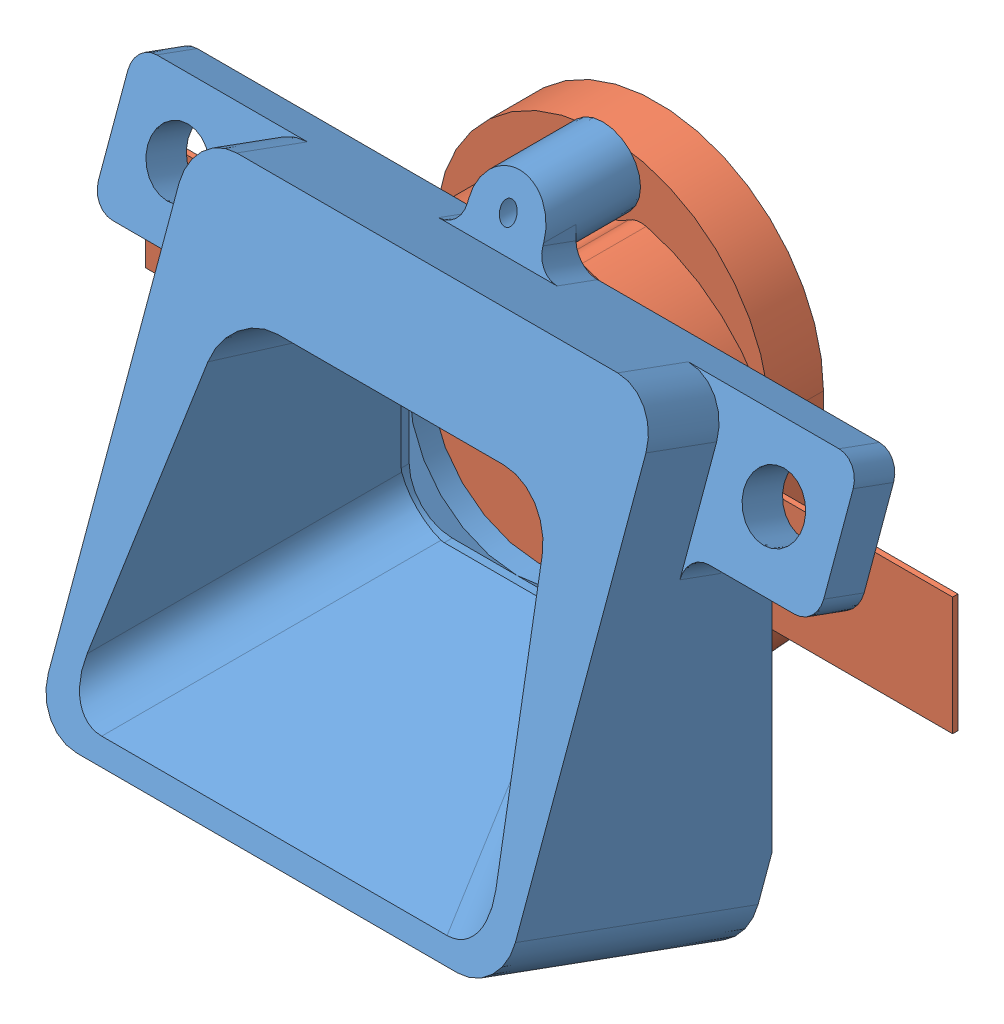
SolidWorks assembly setup_led, configuration Default. Lengths in mm.
Overall size (37.5 26.13 18.1).
2 component instances, 2 part files, 3 mates.
Components (placement in the parent):
- led hoder-1: led hoder [Default] at (21.4895 15.2859 17.3454) size (33.7 26.13 15.6)
- power_led_10W_1-1: power_led_10W_1 [Default] at (41.4895 29.1109 11.8454) x (0 -1 0) z (0 0 1) size (21.6 37.5 5.5)
Mates (geometry in assembly coordinates):
- Coincident1: coincident: plane of led hoder-1 through (21.4895 15.2859 17.3454) normal (0 0 -1); plane of power_led_10W_1-1 through (41.4895 26.0609 17.3454) normal (0 0 1)
- Concentric1: concentric: cylinder of led hoder-1 through (41.4895 26.0609 17.3454) axis (0 0 1) radius 5; circle of power_led_10W_1-1
- Parallel1: parallel: plane of power_led_10W_1-1 through (33.7395 29.1109 14.3454) normal (-1 0 0); plane of led hoder-1 through (30.6394 30.2216 7.4152) normal (-1 0 0)
